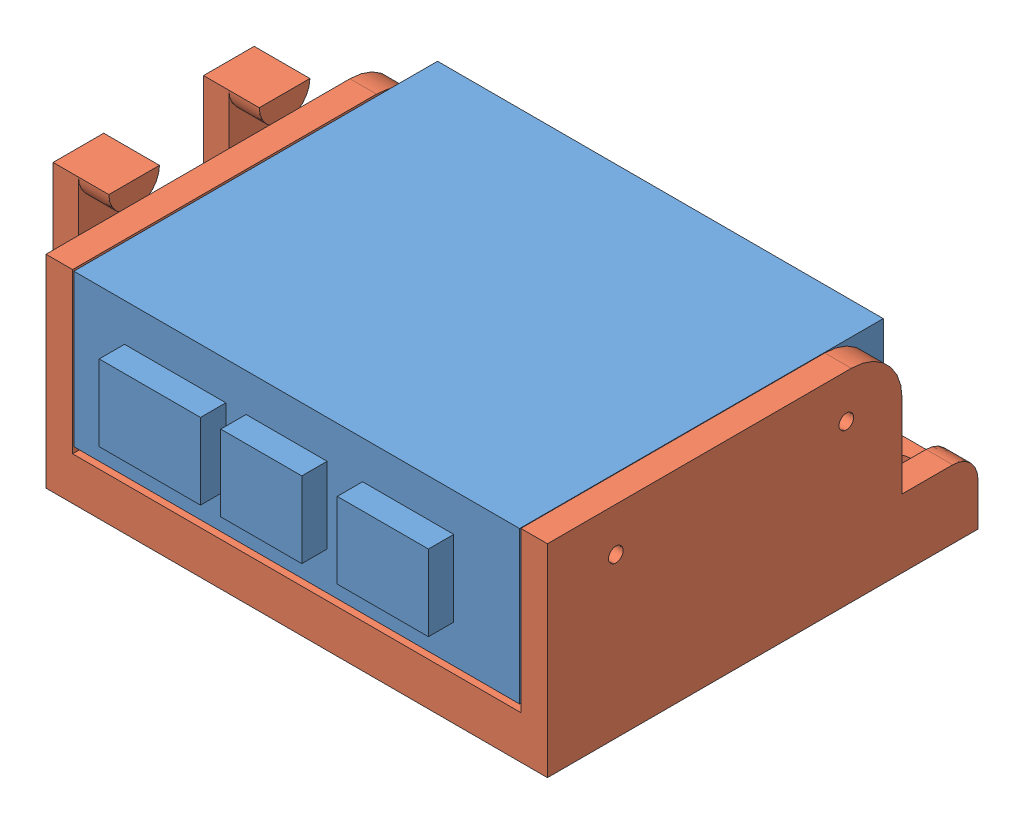
SolidWorks assembly LiDAR Driver Mount Assem, configuration Default. Lengths in mm.
Overall size (114 40 89.75).
2 component instances, 2 part files, 3 mates.
Components (placement in the parent):
- Driver-1: Driver [Default] at (1.9051 -17.9483 85.5) size (88 30 76.8)
- Driver Mount-1: Driver Mount [Default] at (2.1551 -27.5483 79.15) x (-1 0 0) z (0 0 -1) size (114 40 85)
Mates (geometry in assembly coordinates):
- Coincident6: coincident anti-aligned: plane of Driver-1 through (-42.0949 12.0517 121.4) normal (-1 0 0); plane of Driver Mount-1 through (-42.0949 -19.0483 36.65) normal (1 0 0)
- Parallel2: parallel anti-aligned: plane of Driver-1 through (1.9051 -17.9483 85.5) normal (0 -1 0); plane of Driver Mount-1 through (2.1551 -19.0483 79.15) normal (0 1 0)
- Concentric4: concentric aligned: circle of Driver-1; circle of Driver Mount-1
